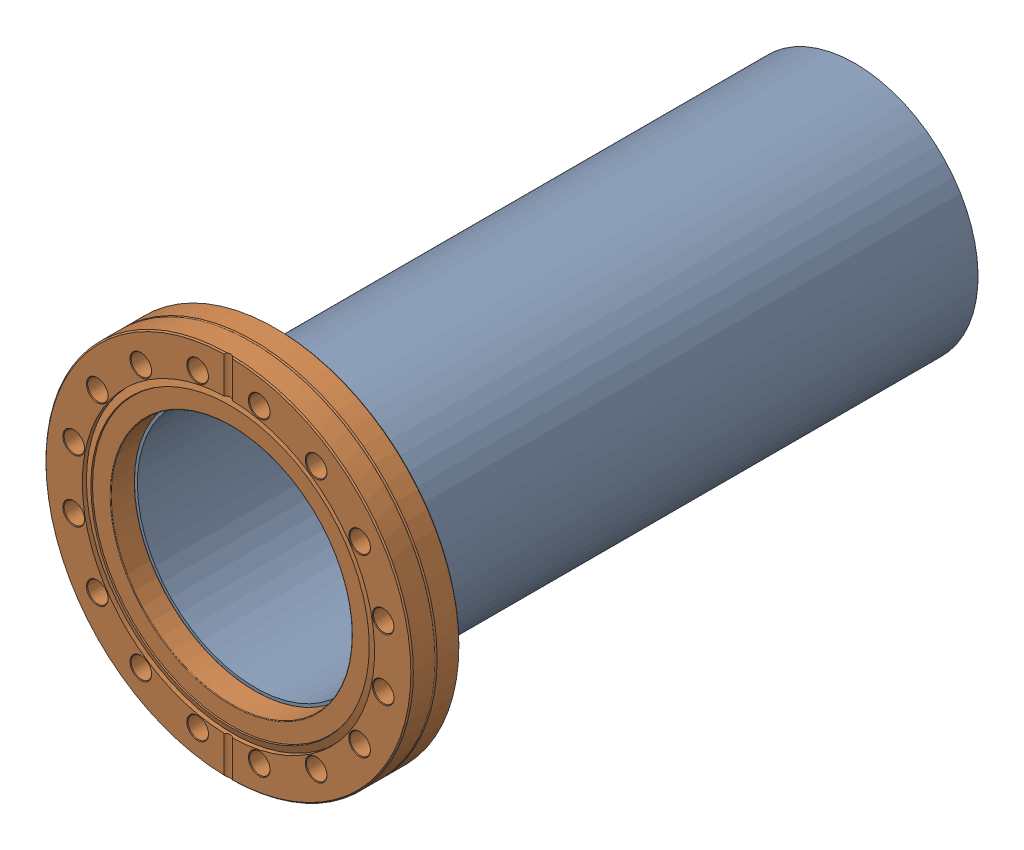
SolidWorks assembly A0001731, configuration Default. Lengths in mm.
Overall size (151.64 151.64 258.78).
2 component instances, 2 part files, 0 mates.
Components (placement in the parent):
- P0001632-1: P0001632 [Default] at (0 0 -124.968) x (0 1 0) z (0 0 -1) size (101.6 101.6 247.55)
- P0000235-1: P0000235 [Default] at origin size (151.64 151.64 19.95)
